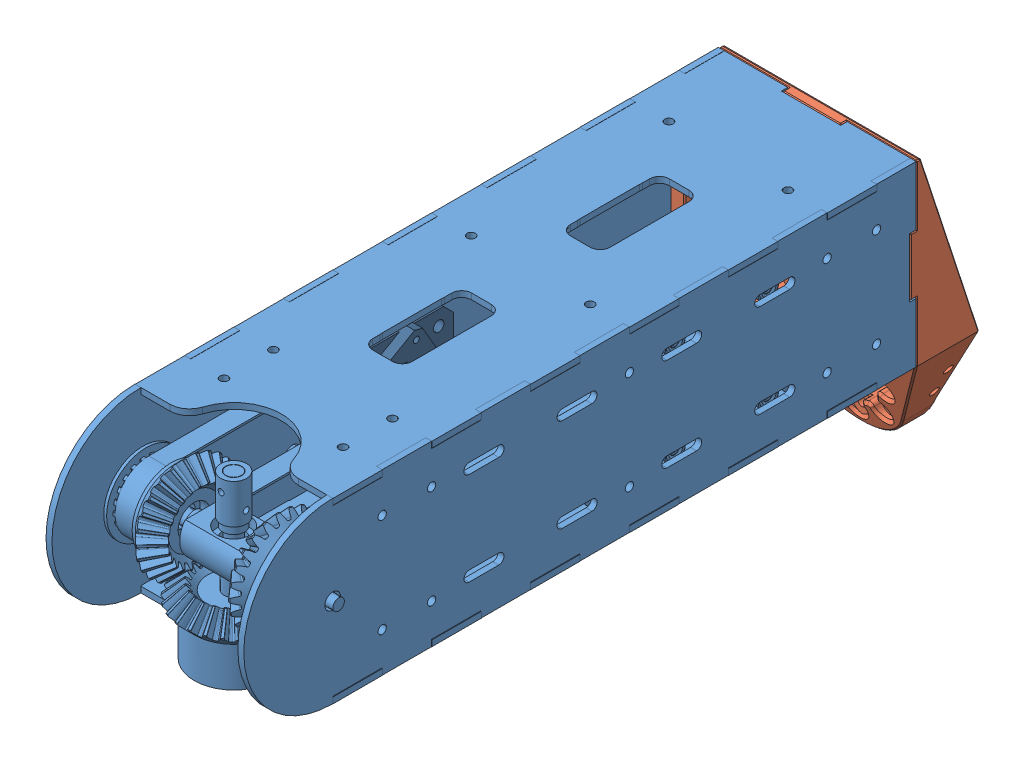
SolidWorks assembly Arm, configuration Default. Lengths in mm.
Overall size (118.18 163.31 372.5).
26 component instances, 12 part files, 12 mates.
Components (placement in the parent):
- Arm CAD-1: Arm CAD [Default] at (-46.1 0 0) x (0 0 1) z (-1 0 0) size (340 95 106)
- Offset Arm Mount-1: Offset Arm Mount [Default] at (0 -75 -327.5) x (1 0 0) z (0 -1 0) size (100 60 150)
- Cycloidal Drive-1: Cycloidal Drive [Default] at (-20.8064 -0.212 -99.8305) x (0 0.866025 0.5) z (-1 0 0) size (85.38 85.38 43.89)
  - Part 4-1: Part 4 [Default] at (1.0989 0.2528 -5.1064) size (35 35 5.4)
  - Part 7-1: Part 7 [Default] at (1.0989 0.2528 -5.1064) size (41.2 41.39 5.79)
  - Part 3-1: Part 3 [Default] at (1.0989 0.2528 -5.1064) size (13 13 11.8)
  - Part 2-1: Part 2 [Default] at (1.0989 0.2528 -5.1064) size (16.5 17.75 5.43)
  - Stepper v6-1: Stepper v6 [Default] at (0.0989 0.2528 27.8936) x (0.5 -0.866025 0) z (0 0 1) size (38 38 18)
  - amt102-v _1_-1: amt102-v _1_ [Default] at origin size (85.38 85.38 9.09)
    - amt102-v_01-1: amt102-v_01 [Default] at (0.0989 0.2528 32.9636) x (0.866025 0.5 0) z (0 0 1) size (62.5 62.5 9.09) (hidden)
    - amt102-v_06-1: amt102-v_06 [Default] at (0.0989 0.2528 32.9636) x (0.866025 0.5 0) z (0 0 1) size (11.92 11.92 7.8) (hidden)
  - Part 6-1: Part 6 [Default] at (1.0989 0.2528 -5.1064) size (13.84 15.43 5.64)
  - Part 1-1: Part 1 [Default] at (1.0989 0.2528 -5.1064) size (38.57 38.73 5.4)
  - Part 5-1: Part 5 [Default] at (1.0989 0.2528 -5.1064) size (79.7 79.7 11.8)
- Cycloidal Drive-2: Cycloidal Drive [Default] at (20.8064 -0.212 -200.1695) x (0 0.866025 -0.5) z (1 0 0) size (85.38 85.38 43.89)
  - Part 4-1: Part 4 [Default] at (1.0989 0.2528 -5.1064) size (35 35 5.4)
  - Part 7-1: Part 7 [Default] at (1.0989 0.2528 -5.1064) size (41.2 41.39 5.79)
  - Part 3-1: Part 3 [Default] at (1.0989 0.2528 -5.1064) size (13 13 11.8)
  - Part 2-1: Part 2 [Default] at (1.0989 0.2528 -5.1064) size (16.5 17.75 5.43)
  - Stepper v6-1: Stepper v6 [Default] at (0.0989 0.2528 27.8936) x (0.5 -0.866025 0) z (0 0 1) size (38 38 18)
  - amt102-v _1_-1: amt102-v _1_ [Default] at origin size (85.38 85.38 9.09)
    - amt102-v_01-1: amt102-v_01 [Default] at (0.0989 0.2528 32.9636) x (0.866025 0.5 0) z (0 0 1) size (62.5 62.5 9.09) (hidden)
    - amt102-v_06-1: amt102-v_06 [Default] at (0.0989 0.2528 32.9636) x (0.866025 0.5 0) z (0 0 1) size (11.92 11.92 7.8) (hidden)
  - Part 6-1: Part 6 [Default] at (1.0989 0.2528 -5.1064) size (13.84 15.43 5.64)
  - Part 1-1: Part 1 [Default] at (1.0989 0.2528 -5.1064) size (38.57 38.73 5.4)
  - Part 5-1: Part 5 [Default] at (1.0989 0.2528 -5.1064) size (79.7 79.7 11.8)
Mates (geometry in assembly coordinates):
- Coincident1: coincident aligned: plane of Arm CAD-1 through (-46.1 0 0) normal (0 1 0)
- Symmetric1: symmetric aligned: plane of Arm CAD-1 through (-50 0 -125) normal (-1 0 0); plane of Arm CAD-1 through (50 0 -125) normal (1 0 0)
- Coincident4: coincident aligned: plane of Arm CAD-1 through (-46.1 0 0) normal (0 0 1)
- Width1: width aligned: plane of Offset Arm Mount-1 through (47 14.75 -295) normal (1 0 0); plane of Offset Arm Mount-1 through (-47 -14.75 -295) normal (-1 0 0); plane of Arm CAD-1 through (-47 0 -125) normal (1 0 0); plane of Arm CAD-1 through (47 0 -125) normal (-1 0 0)
- Width2: width aligned: plane of Offset Arm Mount-1 through (47 42 -295) normal (0 1 0); plane of Offset Arm Mount-1 through (47 -42 -295) normal (0 -1 0); plane of Arm CAD-1 through (0.1 -42 -160) normal (0 1 0); plane of Arm CAD-1 through (0.1 42 -160) normal (0 -1 0)
- Coincident5: coincident anti-aligned: plane of Arm CAD-1 through (-47 45 -295) normal (0 0 -1); plane of Offset Arm Mount-1 through (0 -75 -295) normal (0 0 1)
- Concentric1: concentric anti-aligned: cylinder of Arm CAD-1 through (-40.25 -23.57 -123.57) axis (1 0 0) radius 1.9804; cylinder of Cycloidal Drive-1/Part 5-1 through (-20 -23.57 -123.57) axis (-1 0 0) radius 2.65
- Perpendicular1: perpendicular: plane of Arm CAD-1 through (0.1 45 -160) normal (0 1 0); plane of Cycloidal Drive-1/Part 5-1 through (-20 0 -131.0035) normal (0 0 -1)
- Coincident7: coincident anti-aligned: plane of Arm CAD-1 through (-27 23.57 -76.43) normal (1 0 0); plane of Cycloidal Drive-1/Part 5-1 through (-27 0 -100) normal (-1 0 0)
- Concentric2: concentric aligned: cylinder of Arm CAD-1 through (47 23.57 -176.43) axis (1 0 0) radius 2.5; cylinder of Cycloidal Drive-2/Part 5-1 through (20 23.57 -176.43) axis (1 0 0) radius 2.65
- Parallel2: parallel aligned: plane of Arm CAD-1 through (0.1 45 -160) normal (0 1 0); plane of Cycloidal Drive-2/Part 5-1 through (20 31.0035 -200) normal (0 1 0)
- Coincident9: coincident anti-aligned: plane of Arm CAD-1 through (27 23.57 -176.43) normal (-1 0 0); plane of Cycloidal Drive-2/Part 5-1 through (27 0 -200) normal (1 0 0)
